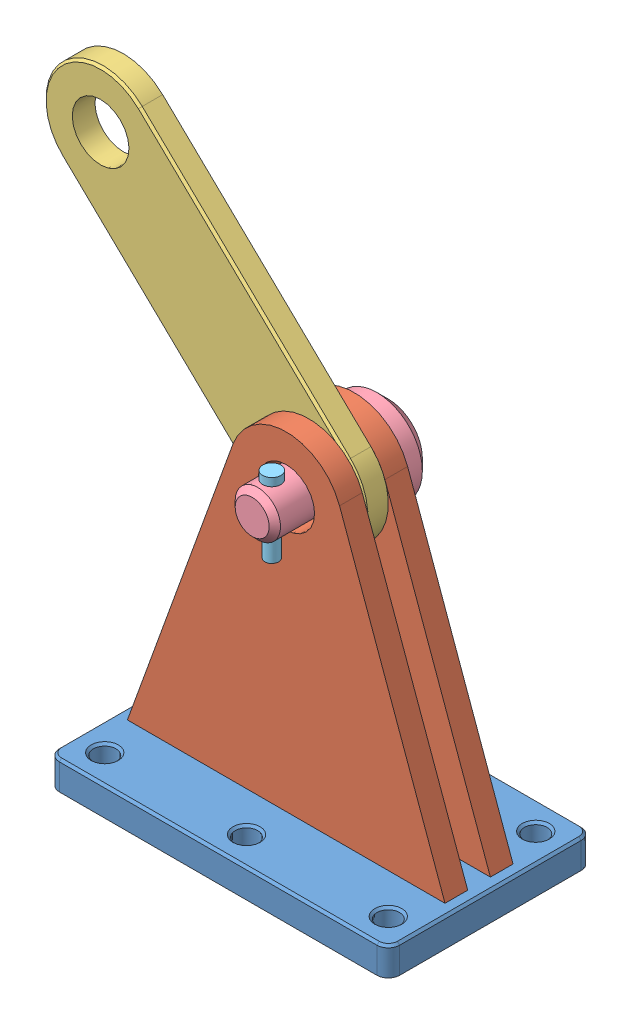
SolidWorks assembly Assem1, configuration Default. Lengths in mm.
Overall size (10269.9 13020.87 4572).
6 component instances, 5 part files, 9 mates.
Components (placement in the parent):
- Part3 0-1: Part3 0 [Default] at (3399.2266 3355.6683 5762.2982) size (7620 635 4572)
- Part1 0-1: Part1 0 [Default] at (3399.2266 7258.0319 5000.2982) size (7112 7366 508)
- Part1 0-2: Part1 0 [Default] at (3399.2266 7258.0319 6016.2982) size (7112 7366 508)
- Part 1-1: Part 1 [Default] at (1067.1497 12333.733 5508.2982) x (-0.69386 -0.72011 0) z (0 0 1) size (2540 9017 508)
- 0-1: 0 [Default] at (3399.2266 10086.6683 4238.2982) x (0 0 1) z (-1 0 0) size (3048 2032 2032)
- Part1 0 0-1: Part1 0 0 [Default] at (3399.2266 9070.6683 6847.2299) size (406.4 1701.8 406.4)
Mates (geometry in assembly coordinates):
- Coincident1: coincident anti-aligned: plane of Part3 0-1 through (-156.7734 3990.6683 7794.2982) normal (0 1 0); plane of Part1 0-1 through (6955.2266 3990.6683 5508.2982) normal (0 -1 0)
- Distance2: distance = 2032 mm anti-aligned: plane of Part1 0-1 through (3399.2266 10086.6683 5508.2982) normal (0 0 1); plane of Part3 0-1 through (-156.7734 3990.6683 3476.2982) normal (0 0 -1)
- Distance3: distance = 254 mm: plane of Part3 0-1 through (7209.2266 3990.6683 3730.2982) normal (1 0 0); line of Part1 0-1 through (6955.2266 3990.6683 5508.2982) axis (0 0 -1)
- Coincident5: coincident anti-aligned: plane of Part1 0-2 through (3399.2266 10086.6683 6016.2982) normal (0 0 -1); plane of Part 1-1 through (-1264.9272 14580.7977 6016.2982) normal (0 0 1)
- Concentric3: concentric aligned: cylinder of Part1 0-2 through (3399.2266 10086.6683 6016.2982) axis (0 0 1) radius 635; cylinder of Part 1-1 through (3399.2266 10086.6683 5508.2982) axis (0 0 1) radius 635
- Concentric4: concentric anti-aligned: circle of Part1 0-2; cylinder of 0-1 through (3399.2266 10086.6683 4238.2982) axis (0 0 -1) radius 508
- Coincident6: coincident anti-aligned: plane of Part1 0-1 through (3399.2266 10086.6683 5000.2982) normal (0 0 -1); plane of 0-1 through (3399.2266 10594.6683 5000.2982) normal (0 0 1)
- Concentric5: concentric anti-aligned: cylinder of 0-1 through (3399.2266 9070.6683 6847.2299) axis (0 1 0) radius 152.4; cylinder of Part1 0 0-1 through (3399.2266 10594.6683 6847.2299) axis (0 -1 0) radius 152.4
- Tangent1: tangent anti-aligned: cylinder of 0-1 through (3399.2266 10086.6683 4238.2982) axis (0 0 -1) radius 508; plane of Part1 0 0-1 through (3399.2266 10594.6683 6847.2299) normal (0 -1 0)
